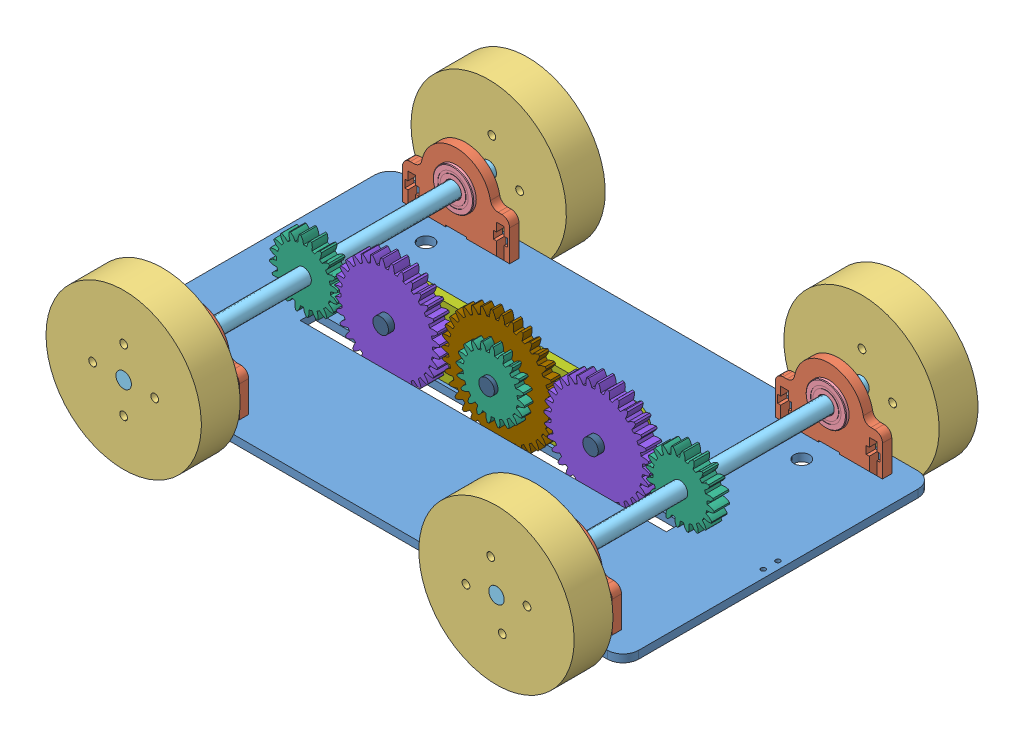
SolidWorks assembly Assem2, configuration Default. Lengths in mm.
Overall size (356.96 116.89 260).
25 component instances, 10 part files, 50 mates.
Components (placement in the parent):
- base-1: base [Default] at (109.1143 152.6703 309.9976) x (0 0 1) z (0 -1 0) size (200 350 5)
- support-1: support [Default] at (-22.3857 177.6703 393.9976) size (69 52.5 6)
- support-2: support [Default] at (-22.3857 177.6703 219.9976) size (69 52.5 6)
- support-3: support [Default] at (217.6343 177.6703 219.9976) size (69 52.5 6)
- support-4: support [Default] at (217.6343 177.6703 393.9976) size (69 52.5 6)
- driving wheel-1: driving wheel [Default] at (217.6343 177.6703 179.9976) x (0.999894 -0.014554 0) z (0 0 1) size (100 100 25)
- driving wheel-2: driving wheel [Default] at (217.6343 177.6703 414.9976) x (0.982476 0.18639 0) z (0 0 1) size (100 100 25)
- driving wheel-3: driving wheel [Default] at (-22.3857 177.6703 414.9976) size (100 100 25)
- driving wheel-4: driving wheel [Default] at (-22.3857 177.6703 179.9976) x (0.994729 -0.102536 0) z (0 0 1) size (100 100 25)
- SS 6000 2RS Double sealed ball bearing 8 X 10 X 26mm-1: SS 6000 2RS Double sealed ball bearing 8 X 10 X 26mm [6661K83] at (217.6343 177.6703 223.9976) size (26 26 8)
- SS 6000 2RS Double sealed ball bearing 8 X 10 X 26mm-2: SS 6000 2RS Double sealed ball bearing 8 X 10 X 26mm [6661K83] at (217.6343 177.6703 395.9976) size (26 26 8)
- SS 6000 2RS Double sealed ball bearing 8 X 10 X 26mm-3: SS 6000 2RS Double sealed ball bearing 8 X 10 X 26mm [6661K83] at (-22.3857 177.6703 395.9976) size (26 26 8)
- SS 6000 2RS Double sealed ball bearing 8 X 10 X 26mm-4: SS 6000 2RS Double sealed ball bearing 8 X 10 X 26mm [6661K83] at (-22.3857 177.6703 223.9976) size (26 26 8)
- rod-1: rod [Default] at (217.6343 177.6703 309.9976) x (-0.891795 0.45244 0) z (0 0 1) size (10 10 260)
- rod-2: rod [Default] at (-22.3857 177.6703 309.9976) x (0.692292 -0.721617 0) z (0 0 1) size (10 10 260)
- gear1-1: gear1 [ISO - Spur gear 2M 20T 20PA 10FW ---S20A75H50L10.0N] at (217.6343 177.6703 321.8651) x (0 0 -1) z (-0.071863 0.997414 0) size (10 43.61 43.61)
- gear1-2: gear1 [ISO - Spur gear 2M 20T 20PA 10FW ---S20A75H50L10.0N] at (-22.3857 177.6703 314.1654) x (0 0 1) z (-0.998457 0.055526 0) size (10 43.61 43.61)
- gearboard-1: gearboard [Default] at (94.1143 172.6703 306.9976) size (180 50 6)
- gearForGearBoard-2: gearForGearBoard [gearForGearBoard] at (165.1643 177.6703 322.9976) x (0 0 -1) z (0.992719 -0.120453 0) size (10 67.78 67.78)
- gearForGearBoard-3: gearForGearBoard [gearForGearBoard] at (30.0643 177.6703 322.9976) x (0 0 -1) z (1 0 0) size (10 67.78 67.78)
- ISO - Spur gear 2M 35T 20PA 6FW ---S35A75H50L10.0N-1: ISO - Spur gear 2M 35T 20PA 6FW ---S35A75H50L10.0N [ISO - Spur gear 2M 35T 20PA 6FW ---S35A75H50L10.0N] at (98.2643 177.6703 312.9976) x (0 0 1) z (-0.44042 -0.897792 0) size (6 73.9 73.97)
- rod2-1: rod2 [Default] at (98.2643 177.6703 306.9976) size (10 10 20)
- rod2-2: rod2 [Default] at (30.0643 177.6703 306.9976) size (10 10 20)
- rod2-3: rod2 [Default] at (165.1643 177.6703 306.9976) size (10 10 20)
- gear1-3: gear1 [ISO - Spur gear 2M 20T 20PA 10FW ---S20A75H50L10.0N] at (98.2643 177.6703 324.6442) x (0 0 -1) z (-0.091611 0.995795 0) size (10 43.61 43.61)
Mates (geometry in assembly coordinates):
- Coincident1: coincident aligned: plane of base-1 through (109.1143 147.6703 309.9976) normal (0 -1 0); plane of support-4 through (195.1343 147.6703 399.9976) normal (0 -1 0)
- Coincident3: coincident anti-aligned: plane of base-1 through (183.1343 152.6703 399.9976) normal (0 0 -1); plane of support-4 through (217.6343 177.6703 399.9976) normal (0 0 1)
- Coincident4: coincident aligned: plane of base-1 through (109.1143 147.6703 309.9976) normal (0 -1 0); plane of support-1 through (-15.6785 147.6703 399.9976) normal (0 -1 0)
- Coincident5: coincident anti-aligned: plane of base-1 through (-15.8257 152.6703 399.9976) normal (0 0 -1); plane of support-1 through (-22.3857 177.6703 399.9976) normal (0 0 1)
- Coincident7: coincident aligned: plane of base-1 through (109.1143 147.6703 309.9976) normal (0 -1 0); plane of support-2 through (-15.6785 147.6703 225.9976) normal (0 -1 0)
- Coincident8: coincident anti-aligned: plane of base-1 through (-15.8257 152.6703 225.9976) normal (0 0 -1); plane of support-2 through (-22.3857 177.6703 225.9976) normal (0 0 1)
- Coincident10: coincident aligned: plane of base-1 through (109.1143 147.6703 309.9976) normal (0 -1 0); plane of support-3 through (224.3415 147.6703 225.9976) normal (0 -1 0)
- Coincident11: coincident anti-aligned: plane of base-1 through (224.1943 152.6703 225.9976) normal (0 0 -1); plane of support-3 through (217.6343 177.6703 225.9976) normal (0 0 1)
- Concentric1: concentric aligned: cylinder of support-3 through (217.6343 177.6703 225.9976) axis (0 0 -1) radius 13; cylinder of driving wheel-1 through (217.6343 177.6703 204.9976) axis (0 0 -1) radius 5
- Concentric2: concentric aligned: cylinder of support-4 through (217.6343 177.6703 399.9976) axis (0 0 -1) radius 13; cylinder of driving wheel-2 through (217.6343 177.6703 439.9976) axis (0 0 -1) radius 5
- Concentric3: concentric aligned: cylinder of support-2 through (-22.3857 177.6703 225.9976) axis (0 0 -1) radius 13; cylinder of driving wheel-4 through (-22.3857 177.6703 204.9976) axis (0 0 -1) radius 5
- Concentric4: concentric aligned: cylinder of support-1 through (-22.3857 177.6703 399.9976) axis (0 0 -1) radius 13; cylinder of driving wheel-3 through (-22.3857 177.6703 439.9976) axis (0 0 -1) radius 5
- Concentric5: concentric anti-aligned: cylinder of support-1 through (-22.3857 177.6703 399.9976) axis (0 0 -1) radius 13; cylinder of SS 6000 2RS Double sealed ball bearing 8 X 10 X 26mm-3 through (-22.3857 177.6703 399.9976) axis (0 0 1) radius 13
- Coincident13: coincident aligned: plane of support-1 through (-22.3857 177.6703 399.9976) normal (0 0 1); plane of SS 6000 2RS Double sealed ball bearing 8 X 10 X 26mm-3 through (-22.3857 187.4603 399.9976) normal (0 0 1)
- Concentric6: concentric anti-aligned: cylinder of support-4 through (217.6343 177.6703 399.9976) axis (0 0 -1) radius 13; cylinder of SS 6000 2RS Double sealed ball bearing 8 X 10 X 26mm-2 through (217.6343 177.6703 399.9976) axis (0 0 1) radius 13
- Coincident14: coincident aligned: plane of support-4 through (217.6343 177.6703 399.9976) normal (0 0 1); plane of SS 6000 2RS Double sealed ball bearing 8 X 10 X 26mm-2 through (217.6343 187.4603 399.9976) normal (0 0 1)
- Concentric7: concentric anti-aligned: cylinder of support-3 through (217.6343 177.6703 225.9976) axis (0 0 -1) radius 13; cylinder of SS 6000 2RS Double sealed ball bearing 8 X 10 X 26mm-1 through (217.6343 177.6703 227.9976) axis (0 0 1) radius 13
- Coincident15: coincident aligned: plane of support-3 through (217.6343 177.6703 219.9976) normal (0 0 -1); plane of SS 6000 2RS Double sealed ball bearing 8 X 10 X 26mm-1 through (217.6343 187.4603 219.9976) normal (0 0 -1)
- Concentric8: concentric anti-aligned: cylinder of support-2 through (-22.3857 177.6703 225.9976) axis (0 0 -1) radius 13; cylinder of SS 6000 2RS Double sealed ball bearing 8 X 10 X 26mm-4 through (-22.3857 177.6703 227.9976) axis (0 0 1) radius 13
- Coincident16: coincident aligned: plane of support-2 through (-22.3857 177.6703 219.9976) normal (0 0 -1); plane of SS 6000 2RS Double sealed ball bearing 8 X 10 X 26mm-4 through (-22.3857 187.4603 219.9976) normal (0 0 -1)
- Concentric9: concentric anti-aligned: cylinder of SS 6000 2RS Double sealed ball bearing 8 X 10 X 26mm-2 through (217.6343 177.6703 399.9976) axis (0 0 1) radius 5; cylinder of rod-1 through (217.6343 177.6703 179.9976) axis (0 0 -1) radius 5
- Coincident17: coincident aligned: plane of base-1; plane of rod-1 through (217.6343 177.6703 309.9976) normal (0 0 1)
- Concentric10: concentric aligned: cylinder of SS 6000 2RS Double sealed ball bearing 8 X 10 X 26mm-3 through (-22.3857 177.6703 399.9976) axis (0 0 1) radius 5; cylinder of rod-2 through (-22.3857 177.6703 179.9976) axis (0 0 1) radius 5
- Coincident18: coincident aligned: plane of base-1; plane of rod-2 through (-22.3857 177.6703 309.9976) normal (0 0 1)
- Coincident19: coincident aligned: plane of driving wheel-4 through (-22.3857 177.6703 179.9976) normal (0 0 -1); plane of rod-2 through (-22.3857 177.6703 179.9976) normal (0 0 -1)
- Coincident20: coincident aligned: plane of driving wheel-1 through (217.6343 177.6703 179.9976) normal (0 0 -1); plane of rod-1 through (217.6343 177.6703 179.9976) normal (0 0 -1)
- Coincident21: coincident aligned: plane of driving wheel-3 through (-22.3857 177.6703 439.9976) normal (0 0 1); plane of rod-2 through (-22.3857 177.6703 439.9976) normal (0 0 1)
- Coincident22: coincident aligned: plane of driving wheel-2 through (217.6343 177.6703 439.9976) normal (0 0 1); plane of rod-1 through (217.6343 177.6703 439.9976) normal (0 0 1)
- Coincident23: coincident anti-aligned: plane of base-1 through (-56.8857 152.6703 219.9976) normal (1 0 0); plane of support-2 through (-56.8857 147.6703 225.9976) normal (-1 0 0)
- Coincident24: coincident anti-aligned: plane of base-1 through (-56.8857 152.6703 393.9976) normal (1 0 0); plane of support-1 through (-56.8857 147.6703 399.9976) normal (-1 0 0)
- Coincident25: coincident anti-aligned: plane of base-1 through (183.1343 152.6703 219.9976) normal (1 0 0); plane of support-3 through (183.1343 147.6703 225.9976) normal (-1 0 0)
- Coincident26: coincident anti-aligned: plane of base-1 through (183.1343 152.6703 393.9976) normal (1 0 0); plane of support-4 through (183.1343 147.6703 399.9976) normal (-1 0 0)
- Concentric111: concentric aligned: cylinder of rod-1 through (217.6343 177.6703 179.9976) axis (0 0 1) radius 5; cylinder of gear1-1 through (217.6343 177.6703 271.8651) axis (0 0 1) radius 5
- Concentric12: concentric anti-aligned: cylinder of rod-2 through (-22.3857 177.6703 179.9976) axis (0 0 1) radius 5; cylinder of gear1-2 through (-22.3857 177.6703 364.1654) axis (0 0 -1) radius 5
- Coincident27: coincident aligned: plane of base-1 through (109.1143 147.6703 309.9976) normal (0 -1 0); plane of gearboard-1 through (184.1143 147.6703 312.9976) normal (0 -1 0)
- Coincident28: coincident anti-aligned: plane of base-1 through (184.1143 157.6703 312.9976) normal (0 0 -1); plane of gearboard-1 through (94.1143 172.6703 312.9976) normal (0 0 1)
- Coincident29: coincident anti-aligned: plane of base-1 through (4.1143 157.6703 312.9976) normal (1 0 0); plane of gearboard-1 through (4.1143 147.6703 312.9976) normal (-1 0 0)
- Concentric13: concentric aligned: cylinder of gearboard-1 through (30.0643 177.6703 306.9976) axis (0 0 1) radius 5; cylinder of gearForGearBoard-3 through (30.0643 177.6703 272.9976) axis (0 0 1) radius 5
- Concentric15: concentric aligned: cylinder of gearboard-1 through (165.1643 177.6703 306.9976) axis (0 0 1) radius 5; cylinder of gearForGearBoard-2 through (165.1643 177.6703 272.9976) axis (0 0 1) radius 5
- Coincident30: coincident anti-aligned: plane of gearboard-1 through (94.1143 172.6703 312.9976) normal (0 0 1); plane of gearForGearBoard-2 through (165.1643 177.6703 312.9976) normal (0 0 -1)
- Coincident32: coincident anti-aligned: plane of gearboard-1 through (94.1143 172.6703 312.9976) normal (0 0 1); plane of gearForGearBoard-3 through (30.0643 177.6703 312.9976) normal (0 0 -1)
- Concentric16: concentric anti-aligned: cylinder of gearboard-1 through (98.2643 177.6703 306.9976) axis (0 0 1) radius 5; cylinder of ISO - Spur gear 2M 35T 20PA 6FW ---S35A75H50L10.0N-1 through (98.2643 177.6703 362.9977) axis (0 0 -1) radius 5
- Coincident33: coincident anti-aligned: plane of gearboard-1 through (94.1143 172.6703 312.9976) normal (0 0 1); plane of ISO - Spur gear 2M 35T 20PA 6FW ---S35A75H50L10.0N-1 through (98.2643 177.6703 312.9976) normal (0 0 -1)
- Concentric17: concentric anti-aligned: cylinder of gearForGearBoard-2 through (165.1643 177.6703 272.9976) axis (0 0 1) radius 5; cylinder of rod2-3 through (165.1643 177.6703 326.9976) axis (0 0 -1) radius 5
- Concentric18: concentric aligned: cylinder of ISO - Spur gear 2M 35T 20PA 6FW ---S35A75H50L10.0N-1 through (98.2643 177.6703 362.9977) axis (0 0 -1) radius 5; cylinder of rod2-1 through (98.2643 177.6703 326.9976) axis (0 0 -1) radius 5
- Coincident34: coincident anti-aligned: circle of gearForGearBoard-3; cylinder of rod2-2 through (30.0643 177.6703 326.9976) axis (0 0 -1) radius 5
- Coincident35: coincident aligned: plane of gearboard-1 through (94.1143 172.6703 306.9976) normal (0 0 -1); plane of rod2-2 through (30.0643 177.6703 306.9976) normal (0 0 -1)
- Coincident36: coincident aligned: plane of gearboard-1 through (94.1143 172.6703 306.9976) normal (0 0 -1); plane of rod2-1 through (98.2643 177.6703 306.9976) normal (0 0 -1)
- Coincident37: coincident aligned: plane of gearboard-1 through (94.1143 172.6703 306.9976) normal (0 0 -1); plane of rod2-3 through (165.1643 177.6703 306.9976) normal (0 0 -1)
- Concentric19: concentric anti-aligned: cylinder of rod2-1 through (98.2643 177.6703 326.9976) axis (0 0 -1) radius 5; cylinder of gear1-3 through (98.2643 177.6703 274.6441) axis (0 0 1) radius 5
